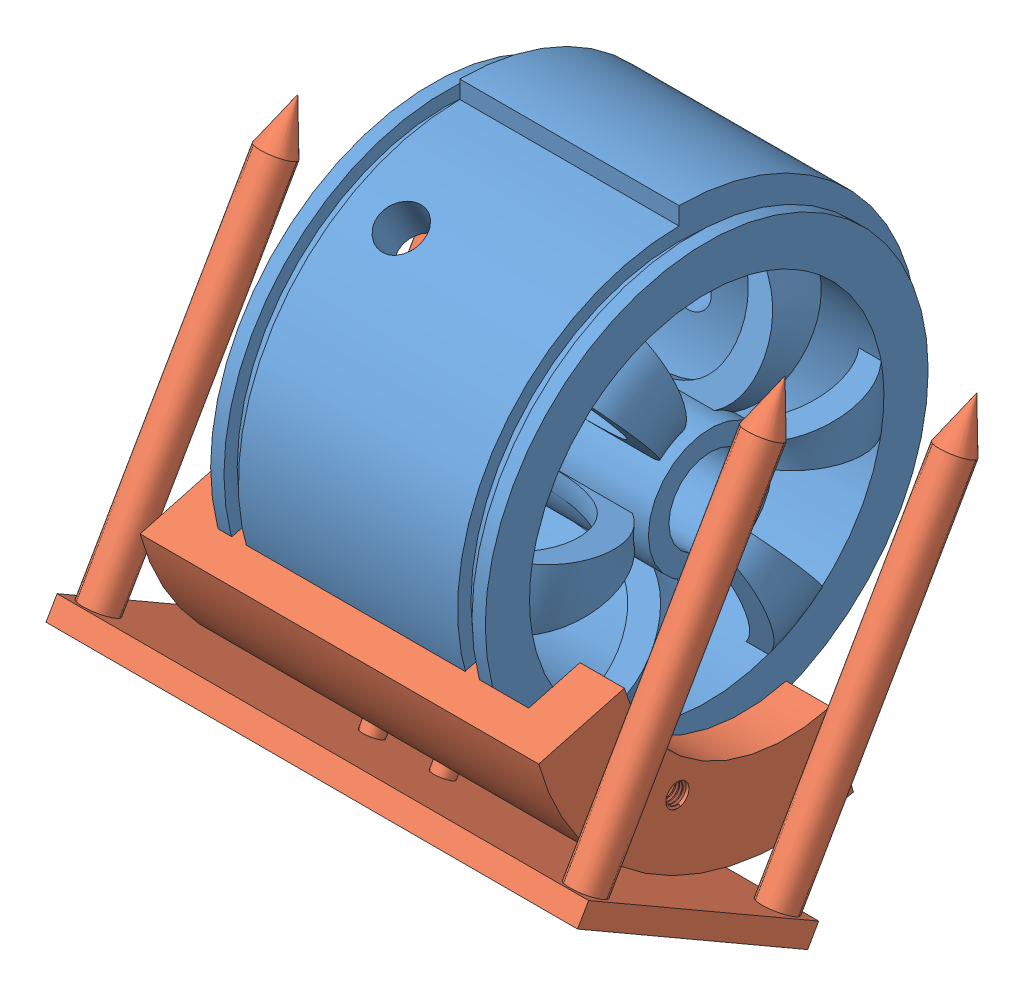
SolidWorks assembly final_substrate, configuration Default. Lengths in mm.
Overall size (120 135.73 129.9).
2 component instances, 2 part files, 3 mates.
Components (placement in the parent):
- Wheel_final_2[2492]-1: Wheel_final_2[2492] [Default] at (26.5478 73.1554 73.4765) size (67.85 104 103.18)
- substrate_bipen-3: substrate_bipen [Default] at (26.5478 73.1554 73.4765) x (-1 0 0) z (0 0.965926 0.258819) size (120 106.07 106.07)
Mates (geometry in assembly coordinates):
- Concentric10: concentric aligned: cylinder of Wheel_final_2[2492]-1 through (13.5478 14.0048 107.6271) axis (0 0.866025 -0.5) radius 5; cylinder of substrate_bipen-3 through (13.5478 22.9242 102.4775) axis (0 0.866025 -0.5) radius 4.75
- Parallel2: parallel anti-aligned: plane of Wheel_final_2[2492]-1 through (-4.4522 123.1554 73.4765) normal (-1 0 0); plane of substrate_bipen-3 through (-4.3522 36.4503 63.6413) normal (1 0 0)
- Concentric11: concentric aligned: cylinder of Wheel_final_2[2492]-1 through (26.5478 73.1554 73.4765) axis (-1 0 0) radius 50; cylinder of substrate_bipen-3 through (-44.1259 73.1554 73.4765) axis (-1 0 0) radius 50
